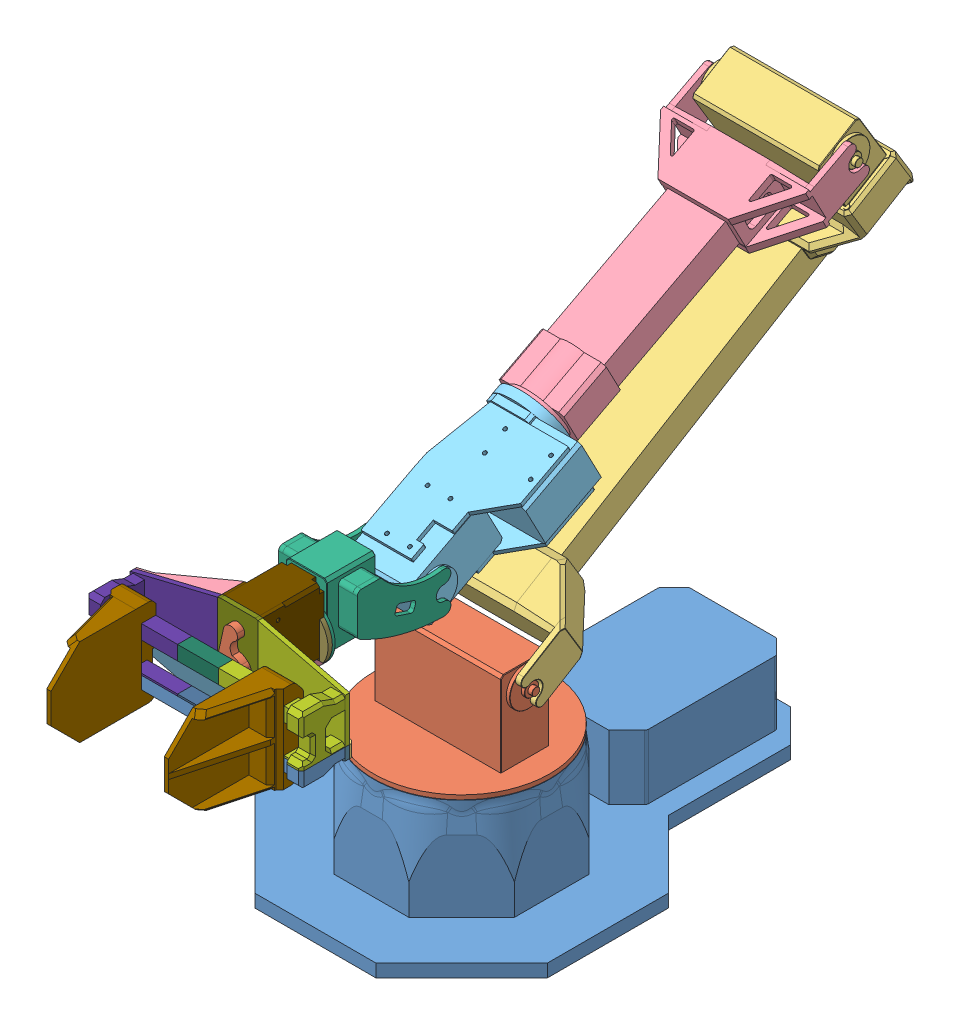
SolidWorks assembly VXA-300-6DOF, configuration Default. Lengths in mm.
Overall size (716.95 357.67 660.08).
24 component instances, 22 part files, 16 mates.
Components (placement in the parent):
- 540 Base v2-1: 540 Base v2 [Default] x (1 0 0) z (0 1 0) size (204 299.46 79.76)
- 540 Dual Shoulder v2-1: 540 Dual Shoulder v2 [Default] at (0 76 -0.6326) x (1 0 0) z (0 1 0) size (123 123 64.5)
- UA - 8 - VX-300 v2-1: UA - 8 - VX-300 v2 [Default] at (0 127.1348 0.2333) x (1 0 0) z (0 0.51836 -0.855162) size (103.81 89.5 327.69)
- SIMPLIFIED - VX300-6DOF Upper Forearm v4-1: SIMPLIFIED - VX300-6DOF Upper Forearm v4 [Default] at (0 333.5678 -225.4472) x (0 -0.88567 -0.464315) z (0 -0.464315 0.88567) size (39 101.22 200.26)
- SIMPLIFIED - VX300-6DOF Lower Forearm v10-1: SIMPLIFIED - VX300-6DOF Lower Forearm v10 [Default] at (0 242.385 -51.5184) x (0 -0.88567 -0.464315) z (0 -0.464315 0.88567) size (46 74.45 117.37)
- VX-300 - Wrist v3-1: VX-300 - Wrist v3 [Default] at (0.1606 194.4337 40.5095) x (1 0 0) z (0 1 0) size (55 75.67 55.64)
- Gripper VX300-1: Gripper VX300 [Default] at (0.1 -232.4769 -319.0405) x (1 0 0) z (0 1 0) size (150 136.7 70.3)
  - DRG v1 (14)-1: DRG v1 (14) [Default] at (-0.1 -409.2943 426.75) size (60.75 33.88 46.01)
  - DRG v1 (15)-1: DRG v1 (15) [Default] at (-0.1 -409.2943 426.75) size (5.75 3 25.28)
  - Carriage-DualRail-VX-ABS v2-1: Carriage-DualRail-VX-ABS v2 [Default] at (-4.599 -457.7943 426.75) x (-1 0 0) z (0 -1 0) size (20.5 61 80.7)
  - DRG v1 (12)-1: DRG v1 (12) [Default] at (-0.1 -409.2943 426.75) size (28.5 10 1.25)
  - DRG v1 (11)-1: DRG v1 (11) [Default] at (-0.1 -409.2943 426.75) size (12.33 5 15.75)
  - DRG v1 (10)-1: DRG v1 (10) [Default] at (-0.1 -409.2943 426.75) size (5.75 3 25.28)
  - DRG v1 (13)-1: DRG v1 (13) [Default] at (-0.1 -409.2943 426.75) size (33.07 3 8.75)
  - DRG v1 (8)-1: DRG v1 (8) [Default] at (-0.1 -409.2943 426.75) size (150 3.17 23.8)
  - DRG v1 (7)-1: DRG v1 (7) [Default] at (-0.1 -409.2943 426.75) size (28.5 10 10)
  - DRG v1 (6)-1: DRG v1 (6) [Default] at (-0.1 -409.2943 426.75) size (28.5 3.17 46.5)
  - DRG v1 (5)-1: DRG v1 (5) [Default] at (-0.1 -409.2943 426.75) size (60.75 33.88 46.01)
  - DRG v1 (4)-1: DRG v1 (4) [Default] at (-0.1 -409.2943 426.75) size (28.5 42.83 46.5)
  - DRG v1 (3)-1: DRG v1 (3) [Default] at (-0.1 -409.2943 426.75) size (150 30.7 11.75)
  - DRG v1 (2)-1: DRG v1 (2) [Default] at (-0.1 -409.2943 426.75) size (19.5 5 38.25)
  - DRG v1 (1)-1: DRG v1 (1) [Default] at (-0.1 -409.2943 426.75) size (150 24.74 24.19)
  - DRG v1-1: DRG v1 [Default] at (-0.1 -409.2943 426.75) size (60.75 25.33 46.01)
  - Carriage-DualRail-VX-ABS v2-2: Carriage-DualRail-VX-ABS v2 [Default] at (4.401 -457.7943 426.75) x (1 0 0) z (0 -1 0) size (20.5 61 80.7)
Mates (geometry in assembly coordinates):
- Distance1: distance = 0.3 mm anti-aligned: plane of 540 Dual Shoulder v2-1 through (0 79 0) normal (0 -1 0); plane of 540 Base v2-1 through (0 78.7 0) normal (0 1 0)
- Concentric1: concentric anti-aligned: circle of 540 Base v2-1; cylinder of 540 Dual Shoulder v2-1 through (0 82 0) axis (0 -1 0) radius 61.5
- Concentric3: concentric anti-aligned: cylinder of 540 Dual Shoulder v2-1 through (-48.9 126.75 0) axis (-1 0 0) radius 2.75; cylinder of UA - 8 - VX-300 v2-1 through (-46.5 126.75 0) axis (1 0 0) radius 6
- Width1: width anti-aligned: plane of 540 Dual Shoulder v2-1 through (-46.6 126.75 0) normal (-1 0 0); plane of 540 Dual Shoulder v2-1 through (46.6 126.75 0) normal (1 0 0); plane of UA - 8 - VX-300 v2-1 through (-46.6 134.5902 -12.9343) normal (1 0 0); plane of UA - 8 - VX-300 v2-1 through (46.6 134.5902 -12.9343) normal (-1 0 0)
- Width2: width anti-aligned: plane of SIMPLIFIED - VX300-6DOF Upper Forearm v4-1 through (46.5 327.5607 -213.9888) normal (-1 0 0); plane of SIMPLIFIED - VX300-6DOF Upper Forearm v4-1 through (-46.5 327.5011 -213.8752) normal (1 0 0); plane of UA - 8 - VX-300 v2-1 through (46.6 333.5678 -225.4472) normal (1 0 0); plane of UA - 8 - VX-300 v2-1 through (-46.6 333.5678 -225.4472) normal (-1 0 0)
- Concentric4: concentric aligned: cylinder of UA - 8 - VX-300 v2-1 through (-49.35 333.5678 -225.4472) axis (1 0 0) radius 5; cylinder of SIMPLIFIED - VX300-6DOF Upper Forearm v4-1 through (-50.6 333.5678 -225.4472) axis (1 0 0) radius 6
- Coincident2: coincident anti-aligned: plane of SIMPLIFIED - VX300-6DOF Upper Forearm v4-1 through (0 242.385 -51.5184) normal (0 -0.464315 0.88567); plane of SIMPLIFIED - VX300-6DOF Lower Forearm v10-1 through (0 242.385 -51.5184) normal (0 0.464315 -0.88567)
- Concentric7: concentric aligned: cylinder of SIMPLIFIED - VX300-6DOF Upper Forearm v4-1 through (0 243.7826 -54.1843) axis (0 -0.464315 0.88567) radius 19.5; cylinder of SIMPLIFIED - VX300-6DOF Lower Forearm v10-1 through (0 242.385 -51.5184) axis (0 -0.464315 0.88567) radius 23
- Width3: width anti-aligned: plane of SIMPLIFIED - VX300-6DOF Lower Forearm v10-1 through (-24.5 194.2731 40.2538) normal (-1 0 0); plane of SIMPLIFIED - VX300-6DOF Lower Forearm v10-1 through (24.5 194.2731 40.2538) normal (1 0 0); plane of VX-300 - Wrist v3-1 through (27.5 202.6481 67.6138) normal (1 0 0); plane of VX-300 - Wrist v3-1 through (-27.5 202.6481 67.6138) normal (-1 0 0)
- Concentric8: concentric aligned: cylinder of SIMPLIFIED - VX300-6DOF Lower Forearm v10-1 through (-22 194.2731 40.2538) axis (-1 0 0) radius 13; cylinder of VX-300 - Wrist v3-1 through (-24.5 194.2731 40.2538) axis (-1 0 0) radius 5
- Concentric9: concentric anti-aligned: cylinder of VX-300 - Wrist v3-1 through (0 194.2731 110.2538) axis (0 0 -1) radius 20; cylinder of Gripper VX300-1/DRG v1 (15)-1 through (0 194.2731 110.2538) axis (0 0 1) radius 20
- Coincident4: coincident anti-aligned: plane of VX-300 - Wrist v3-1 through (0 194.2731 110.2538) normal (0 0 1); plane of Gripper VX300-1/DRG v1 (15)-1 through (0 201.8981 110.2538) normal (0 0 -1)
- Coincident5: coincident aligned: plane of UA - 8 - VX-300 v2-1 through (0 127.1348 0.2333) normal (1 0 0)
- Coincident6: coincident aligned: plane of SIMPLIFIED - VX300-6DOF Lower Forearm v10-1 through (0 242.385 -51.5184) normal (1 0 0)
- Parallel1: parallel aligned: plane of Gripper VX300-1 through (0.1 -232.4769 -319.0405) normal (1 0 0)
- Parallel2: parallel aligned: plane of Gripper VX300-1 through (0.1 -232.4769 -319.0405) normal (0 1 0)
